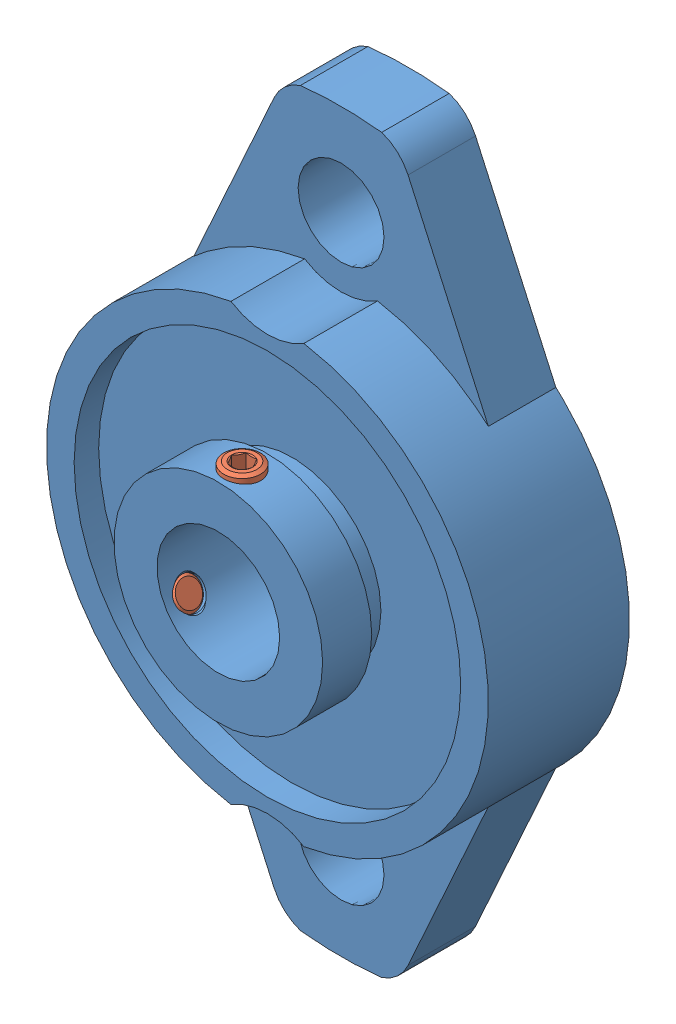
SolidWorks assembly 装配体2, configuration 默认. Lengths in mm.
Overall size (36 60 15.5).
3 component instances, 2 part files, 6 mates.
Components (placement in the parent):
- HBT10x-1: HBT10x [默认] at origin size (36 60 15.5)
- Headless_pin_DIN_913___M3x4-1: Headless_pin_DIN_913___M3x4 [默认] at (0 9 5.8125) x (0 -1 0) z (-1 0 0) size (4.08 3 3)
- Headless_pin_DIN_913___M3x4-2: Headless_pin_DIN_913___M3x4 [默认] at (-7.7942 -4.5 5.8125) x (0.866025 0.5 0) z (-0.5 0.866025 0) size (4.08 3 3)
Mates (geometry in assembly coordinates):
- 距离1: distance = 0 mm anti-aligned: plane of Headless_pin_DIN_913___M3x4-1; plane of HBT10x-1 through (0 5 0) normal (0 1 0)
- 重合1: coincident anti-aligned: line of HBT10x-1 through (0 50 5.8125) axis (0 -1 0); line of Headless_pin_DIN_913___M3x4-1 through (0 -71.9 5.8125) axis (0 1 0)
- 角度3: planar angle = 0 rad aligned: plane of Headless_pin_DIN_913___M3x4-1 through (0 9 5.8125) normal (1 0 0); plane of HBT10x-1 through (0 0 0) normal (1 0 0)
- 距离2: distance = 0 mm anti-aligned: plane of Headless_pin_DIN_913___M3x4-2; plane of HBT10x-1 through (-4.3301 -2.5 0) normal (-0.866025 -0.5 0)
- 重合2: coincident anti-aligned: line of HBT10x-1 through (-70.0615 -40.45 5.8125) axis (0.866025 0.5 0); line of Headless_pin_DIN_913___M3x4-2 through (62.2672 35.95 5.8125) axis (-0.866025 -0.5 0)
- 角度6: planar angle = 0 rad aligned: plane of Headless_pin_DIN_913___M3x4-2; plane of HBT10x-1 through (0 0 0) normal (0.5 -0.866025 0)
